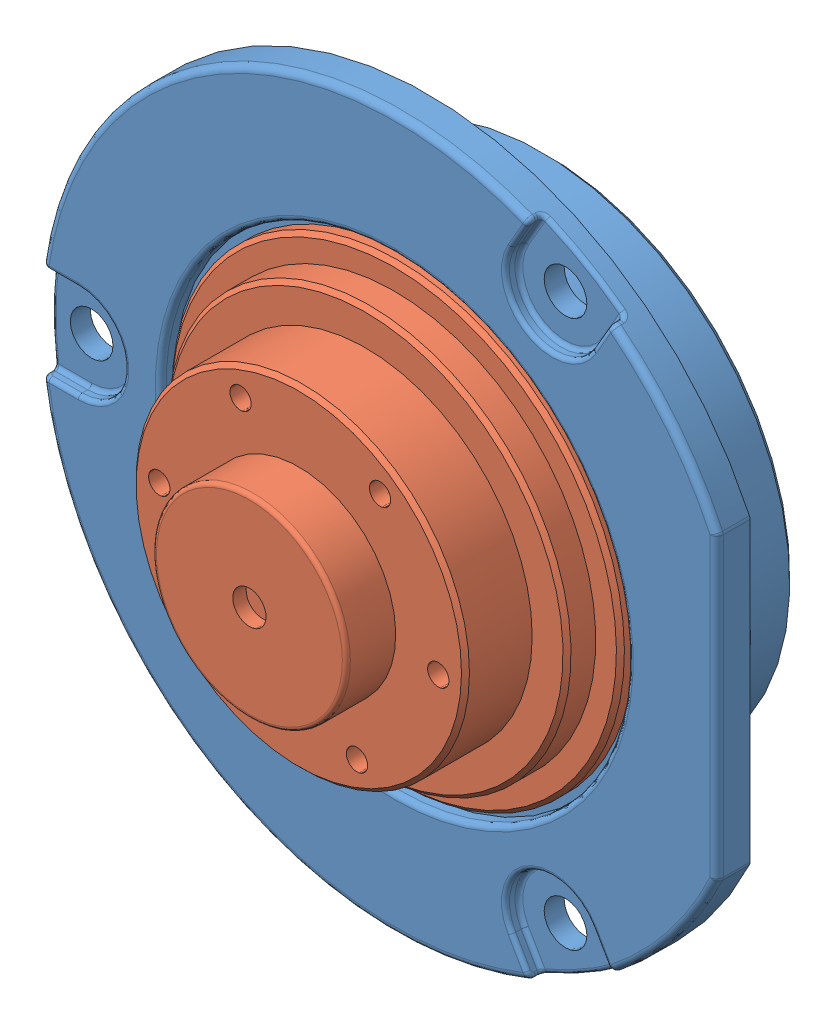
SolidWorks assembly motor, configuration 默认. Lengths in mm.
Overall size (50.8 53.28 22.35).
2 component instances, 2 part files, 2 mates.
Components (placement in the parent):
- motor_stator-1: motor_stator [默认] at (23.6703 0.0786 55.3468) x (1 0 0) z (0 -1 0) size (50.8 11.53 53.28)
- motor_rotor-1: motor_rotor [默认] at (23.6703 0.0786 66.8468) x (-0.580109 -0.814539 0) z (-0.814539 0.580109 0) size (33.9 11.85 33.9)
Mates (geometry in assembly coordinates):
- 重合1: coincident anti-aligned: plane of motor_stator-1 through (23.6703 0.0786 65.8468) normal (0 0 1); plane of motor_rotor-1 through (23.6703 0.0786 65.8468) normal (0 0 -1)
- 同心1: concentric aligned: cylinder of motor_stator-1 through (23.6703 0.0786 66.8468) axis (0 0 -1) radius 26.64; cylinder of motor_rotor-1 through (23.6703 0.0786 73.9968) axis (0 0 -1) radius 12.49
